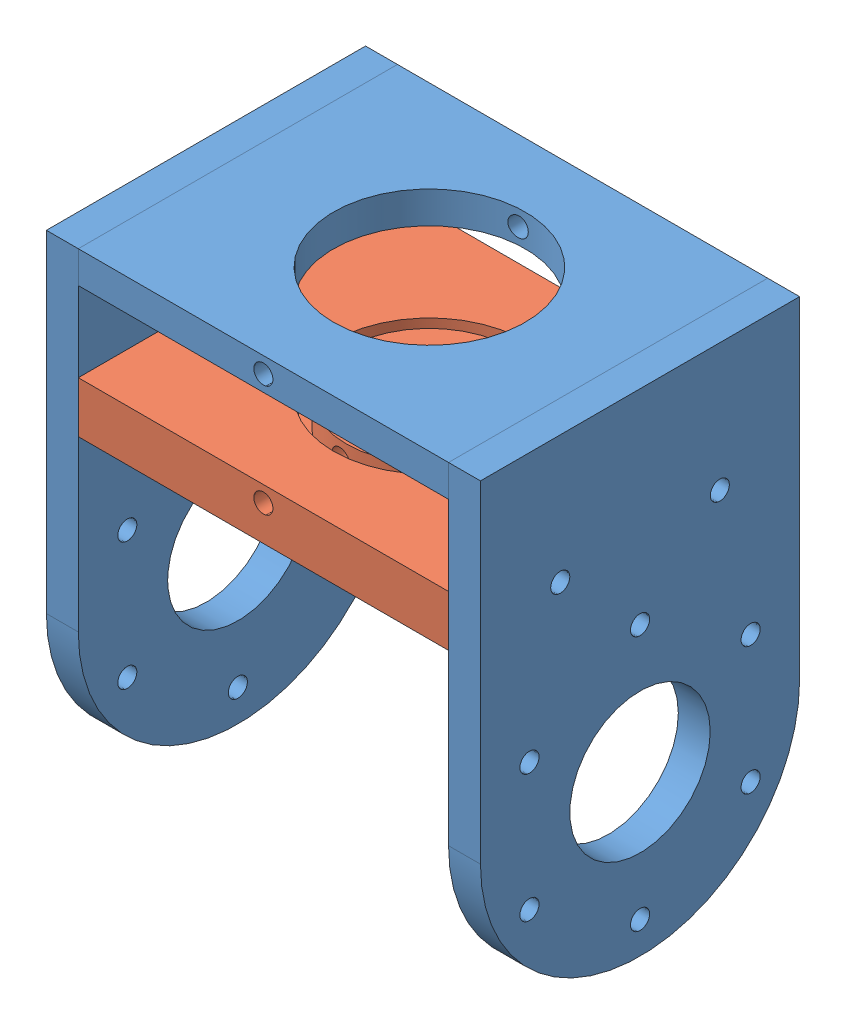
SolidWorks assembly Assemblage_av_bras, configuration Défaut. Lengths in mm.
Overall size (68 77 50).
2 component instances, 2 part files, 3 mates.
Components (placement in the parent):
- Carcasse_av_bras-1: Carcasse_av_bras [Défaut] at (8.602 29.9971 19) size (68 77 50)
- Support_axe_2-1: Support_axe_2 [Défaut] at (-14.8298 67.4646 52) size (58 8 50)
Mates (geometry in assembly coordinates):
- Coaxiale1: concentric: cylinder of Carcasse_av_bras-1 through (42.6702 19.9646 89.5) axis (-1 0 0) radius 1.5; circle of Support_axe_2-1
- Coaxiale2: concentric: cylinder of Carcasse_av_bras-1 through (-20.3298 19.9646 64.5) axis (-1 0 0) radius 1.5; cylinder of Support_axe_2-1 through (-10.3298 19.9646 64.5) axis (-1 0 0) radius 1.5
- Coïncidente2: coincident anti-aligned: plane of Carcasse_av_bras-1 through (-20.3298 -12.0354 77) normal (1 0 0); plane of Support_axe_2-1 through (-20.3298 22.4646 102) normal (-1 0 0)
